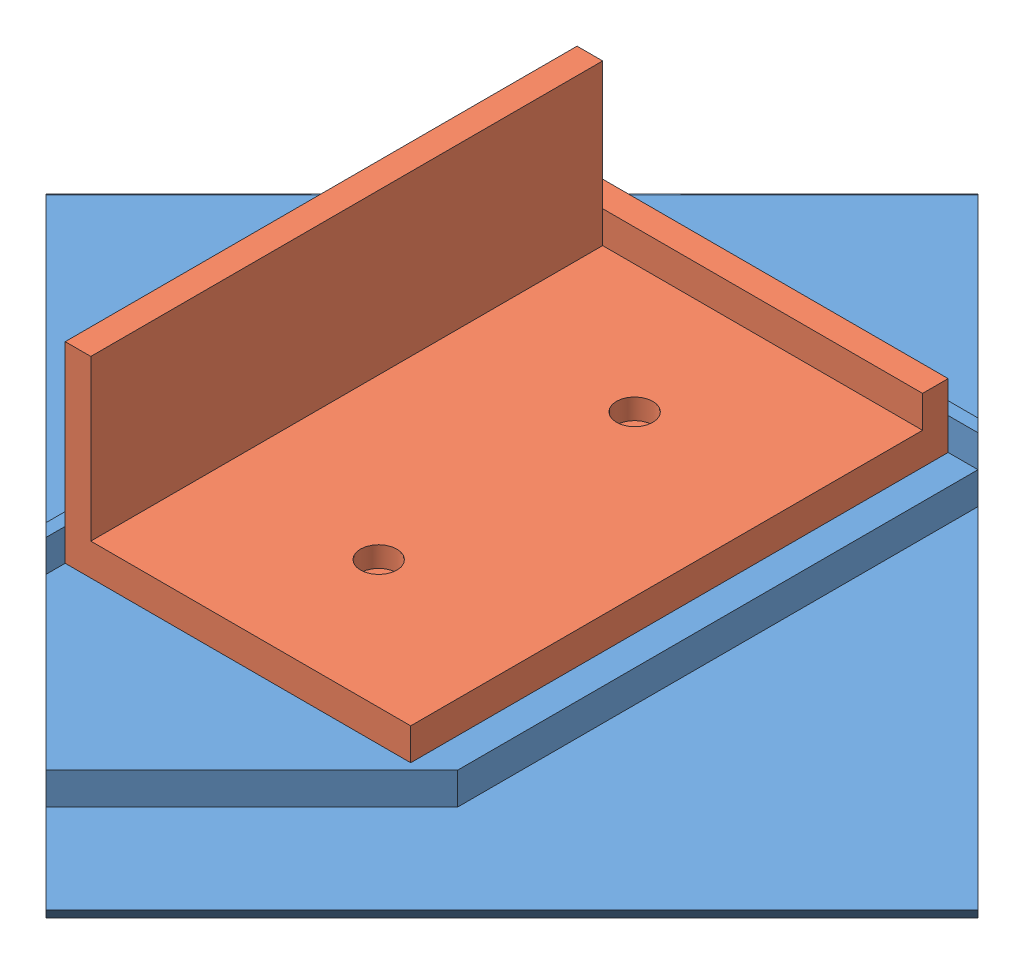
SolidWorks assembly zwischenablage, configuration Standard. Lengths in mm.
Overall size (153.38 113.91 153.38).
2 component instances, 2 part files, 3 mates.
Components (placement in the parent):
- zwischenablage_stand-1: zwischenablage_stand [Standard] at (-39.1117 -67.2285 122.955) x (-0.5 0.707107 -0.5) z (0.707107 0 -0.707107) size (81.61 79.49 103)
- zwischenablagevorrichtung-1: zwischenablagevorrichtung [Standard] at (25.6654 -12.4884 85) size (54 30 84)
Mates (geometry in assembly coordinates):
- Coincident11: coincident anti-aligned: plane of zwischenablage_stand-1 through (69.502 -12.4884 85.9048) normal (0 1 0); plane of zwischenablagevorrichtung-1 through (25.6654 -12.4884 85) normal (0 -1 0)
- Coincident12: coincident anti-aligned: plane of zwischenablage_stand-1 through (-39.1117 -7.4884 45.2368) normal (0 0 1); plane of zwischenablagevorrichtung-1 through (25.6654 -2.4884 45.2368) normal (0 0 -1)
- Coincident13: coincident anti-aligned: plane of zwischenablage_stand-1 through (-29.83 -7.4884 122.955) normal (1 0 0); plane of zwischenablagevorrichtung-1 through (-29.83 -2.4884 85) normal (-1 0 0)
